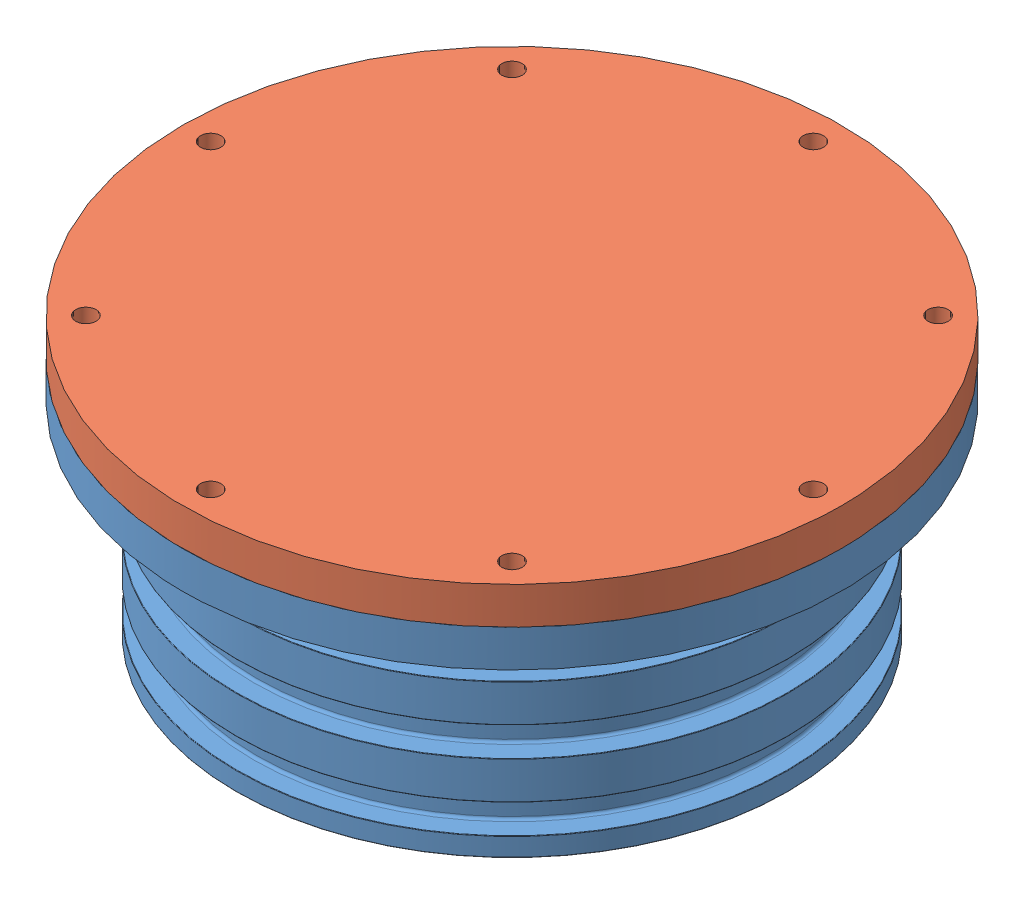
SolidWorks assembly Endcap, configuration Default. Lengths in mm.
Overall size (177.8 74.1 177.8).
2 component instances, 2 part files, 3 mates.
Components (placement in the parent):
- Flange-1: Flange [Default] at (106.0902 76.482 103.3864) size (177.8 64.1 177.8)
- Endcap-1: Endcap [Default] at (106.0902 140.584 103.3864) x (1 0 0) z (0 1 0) size (177.8 177.8 10)
Mates (geometry in assembly coordinates):
- Coincident1: coincident anti-aligned: plane of Flange-1 through (106.0902 140.584 103.3864) normal (0 1 0); plane of Endcap-1 through (106.0902 140.584 103.3864) normal (0 -1 0)
- Coincident2: coincident aligned: circle of Flange-1; circle of Endcap-1
- Concentric1: concentric aligned: circle of Flange-1; circle of Endcap-1
